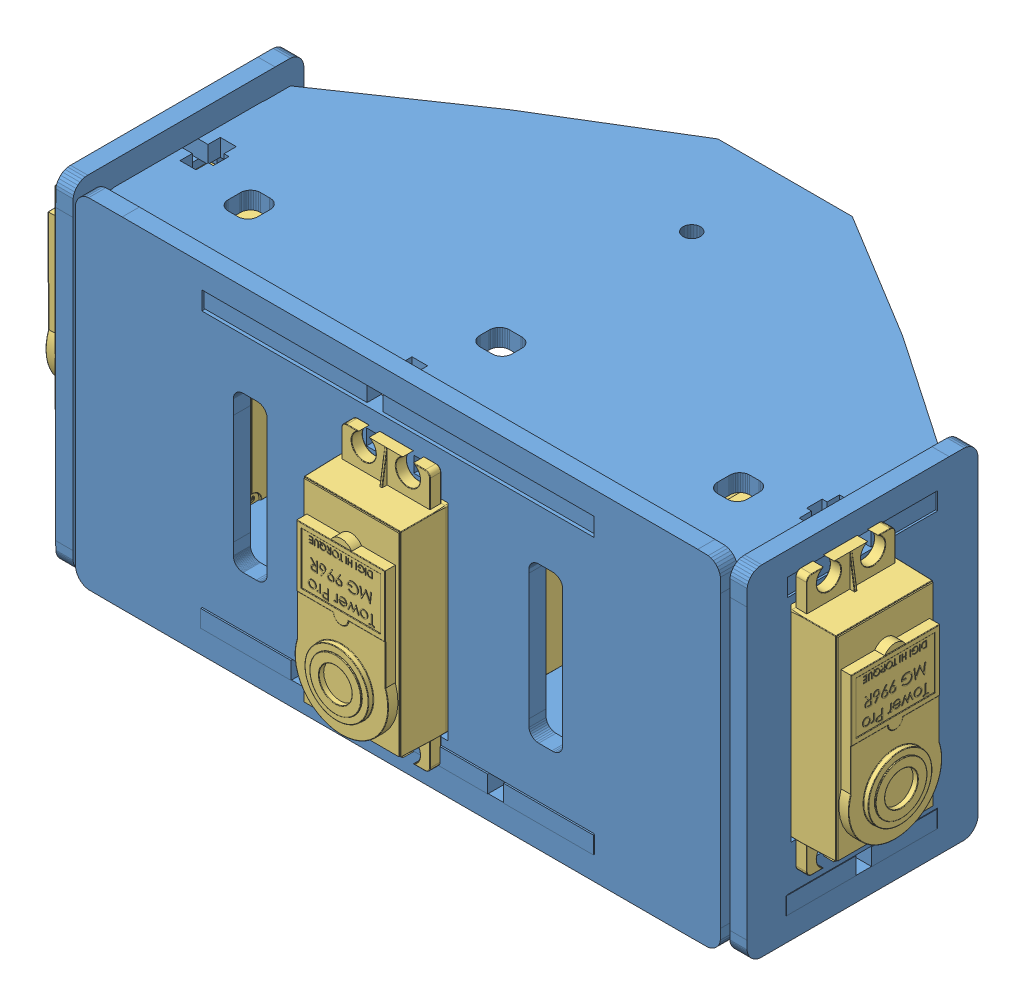
SolidWorks assembly Assem1, configuration Default. Lengths in mm.
Overall size (165.9 69.23 91.58).
8 component instances, 3 part files, 4 mates.
Components (placement in the parent):
- chest_100-1: chest_100 [Default] at origin size (140.92 69.23 79.27)
- servo_arm_6_sided-1: servo_arm_6_sided [Default] at (13.6952 0.0106 19.2103) x (-0.009215 0 -0.999958) z (-0.999958 0 0.009215) size (36.45 6.25 32.2)
- main_assembly-1: main_assembly [Default] at (25.2039 67.5593 44.4253) x (0.001399 0 0.999999) z (0.999999 0 -0.001399) size (20 53 41.5)
  - main_body-1: main_body [Default] at (15.1003 34.2066 38.7045) size (20 53 41.5)
- main_assembly-2: main_assembly [Default] at (2.1612 67.6631 73.5443) x (-0.017013 0 -0.999855) z (-0.999855 0 0.017013) size (20 53 41.5)
  - main_body-1: main_body [Default] at (15.1003 34.2066 38.7045) size (20 53 41.5)
- main_assembly-3: main_assembly [Default] at (28.6521 60.4748 20.3843) x (-0.999999 0 -0.001518) z (-0.001518 0 0.999999) size (20 53 41.5)
  - main_body-1: main_body [Default] at (15.1003 34.2066 38.7045) size (20 53 41.5)
Mates (geometry in assembly coordinates):
- ProfileCenter1: profile center anti-aligned: circle of chest_100-1; circle of servo_arm_6_sided-1
- Coincident1: coincident anti-aligned: line of chest_100-1 through (83.9435 12.4648 69.4435) axis (0 1 0); line of main_assembly-1/main_body-1 through (83.9435 53.1027 69.4435) axis (0 -1 0)
- Coincident2: coincident aligned: line of chest_100-1 through (-56.6216 12.5523 69.4435) axis (0 1 0); line of main_assembly-2/main_body-1 through (-56.6216 13.7065 69.4435) axis (0 1 0)
- Coincident3: coincident anti-aligned: line of chest_100-1 through (3.4627 5.1066 79.0507) axis (0 1 0); line of main_assembly-3/main_body-1 through (3.4627 46.0182 79.0507) axis (0 -1 0)
